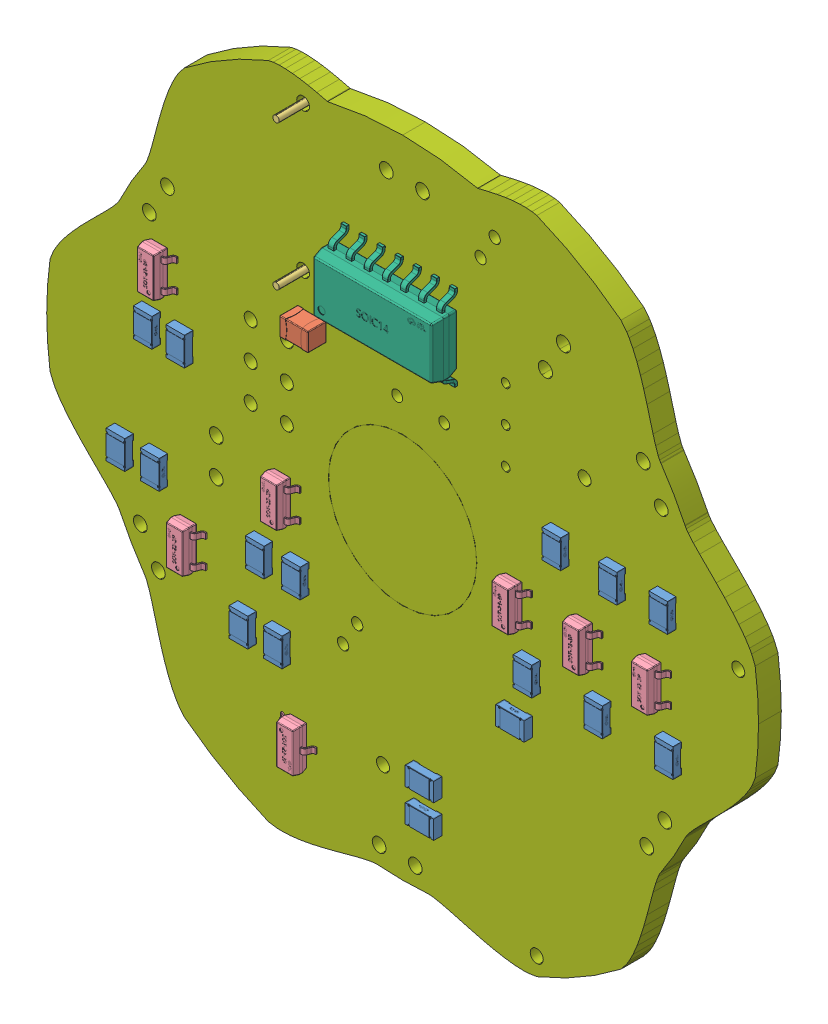
SolidWorks assembly PCB3d, configuration Default. Lengths in mm.
Overall size (49.97 46.56 5.9).
86 component instances, 7 part files, 0 mates.
Components (placement in the parent):
- 3D_PCB_PCB_Segnalatore copy copy_2023-08-18_2023-08-18.step-1: 3D_PCB_PCB_Segnalatore copy copy_2023-08-18_2023-08-18.step [Default] at origin size (49.97 46.56 5.9)
  - R5.step-1: R5.step [Default] at (9.525 -26.0351 1.6) x (-1 0 0) z (0 0 1) size (2 1.3 0.61)
    - R0805.step-1: R0805.step [Default] at origin size (2 1.3 0.61)
      - COMPOUND.step-1: COMPOUND.step [Default] at origin size (2 1.3 0.61)
  - R2.step-1: R2.step [Default] at (9.525 -28.3211 1.6) size (2 1.3 0.61)
    - R0805.step-1: R0805.step [Default] at origin size (2 1.3 0.61)
      - COMPOUND.step-1: COMPOUND.step [Default] at origin size (2 1.3 0.61)
  - R7.step-1: R7.step [Default] at (18.796 -7.112 1.6) x (0 -1 0) z (0 0 1) size (2 1.3 0.61)
    - R0805.step-1: R0805.step [Default] at origin size (2 1.3 0.61)
      - COMPOUND.step-1: COMPOUND.step [Default] at origin size (2 1.3 0.61)
  - R8.step-1: R8.step [Default] at (22.733 -7.239 1.6) x (0 -1 0) z (0 0 1) size (2 1.3 0.61)
    - R0805.step-1: R0805.step [Default] at origin size (2 1.3 0.61)
      - COMPOUND.step-1: COMPOUND.step [Default] at origin size (2 1.3 0.61)
  - R9.step-1: R9.step [Default] at (26.2891 -7.239 1.6) x (0 -1 0) z (0 0 1) size (2 1.3 0.61)
    - R0805.step-1: R0805.step [Default] at origin size (2 1.3 0.61)
      - COMPOUND.step-1: COMPOUND.step [Default] at origin size (2 1.3 0.61)
  - R10.step-1: R10.step [Default] at (-0.762 -22.86 1.6) x (0 -1 0) z (0 0 1) size (2 1.3 0.61)
    - R0805.step-1: R0805.step [Default] at origin size (2 1.3 0.61)
      - COMPOUND.step-1: COMPOUND.step [Default] at origin size (2 1.3 0.61)
  - R11.step-1: R11.step [Default] at (-9.398 -16.383 1.6) x (0 -1 0) z (0 0 1) size (2 1.3 0.61)
    - R0805.step-1: R0805.step [Default] at origin size (2 1.3 0.61)
      - COMPOUND.step-1: COMPOUND.step [Default] at origin size (2 1.3 0.61)
  - R12.step-1: R12.step [Default] at (-7.62 -8.001 1.6) x (0 1 0) z (0 0 1) size (2 1.3 0.61)
    - R0805.step-1: R0805.step [Default] at origin size (2 1.3 0.61)
      - COMPOUND.step-1: COMPOUND.step [Default] at origin size (2 1.3 0.61)
  - R13.step-1: R13.step [Default] at (-2.032 -18.034 1.6) x (0 1 0) z (0 0 1) size (2 1.3 0.61)
    - R0805.step-1: R0805.step [Default] at origin size (2 1.3 0.61)
      - COMPOUND.step-1: COMPOUND.step [Default] at origin size (2 1.3 0.61)
  - R15.step-1: R15.step [Default] at (16.764 -15.875 1.6) x (0 -1 0) z (0 0 1) size (2 1.3 0.61)
    - R0805.step-1: R0805.step [Default] at origin size (2 1.3 0.61)
      - COMPOUND.step-1: COMPOUND.step [Default] at origin size (2 1.3 0.61)
  - R16.step-1: R16.step [Default] at (21.717 -15.875 1.6) x (0 -1 0) z (0 0 1) size (2 1.3 0.61)
    - R0805.step-1: R0805.step [Default] at origin size (2 1.3 0.61)
      - COMPOUND.step-1: COMPOUND.step [Default] at origin size (2 1.3 0.61)
  - R17.step-1: R17.step [Default] at (26.6701 -15.875 1.6) x (0 -1 0) z (0 0 1) size (2 1.3 0.61)
    - R0805.step-1: R0805.step [Default] at origin size (2 1.3 0.61)
      - COMPOUND.step-1: COMPOUND.step [Default] at origin size (2 1.3 0.61)
  - R18.step-1: R18.step [Default] at (-3.175 -22.86 1.6) x (0 1 0) z (0 0 1) size (2 1.3 0.61)
    - R0805.step-1: R0805.step [Default] at origin size (2 1.3 0.61)
      - COMPOUND.step-1: COMPOUND.step [Default] at origin size (2 1.3 0.61)
  - R19.step-1: R19.step [Default] at (-11.811 -16.383 1.6) x (0 1 0) z (0 0 1) size (2 1.3 0.61)
    - R0805.step-1: R0805.step [Default] at origin size (2 1.3 0.61)
      - COMPOUND.step-1: COMPOUND.step [Default] at origin size (2 1.3 0.61)
  - R20.step-1: R20.step [Default] at (-9.906 -8.001 1.6) x (0 -1 0) z (0 0 1) size (2 1.3 0.61)
    - R0805.step-1: R0805.step [Default] at origin size (2 1.3 0.61)
      - COMPOUND.step-1: COMPOUND.step [Default] at origin size (2 1.3 0.61)
  - R21.step-1: R21.step [Default] at (0.508 -18.034 1.6) x (0 -1 0) z (0 0 1) size (2 1.3 0.61)
    - R0805.step-1: R0805.step [Default] at origin size (2 1.3 0.61)
      - COMPOUND.step-1: COMPOUND.step [Default] at origin size (2 1.3 0.61)
  - R22.step-1: R22.step [Default] at (15.875 -19.177 1.6) size (2 1.3 0.61)
    - R0805.step-1: R0805.step [Default] at origin size (2 1.3 0.61)
      - COMPOUND.step-1: COMPOUND.step [Default] at origin size (2 1.3 0.61)
  - C1.step-1: C1.step [Default] at (1.397 -2.413 1.6) x (-1 0 0) z (0 0 1) size (2 1.3 1.3)
    - C0805.step-1: C0805.step [Default] at origin size (2 1.3 1.3)
      - SOLID.step-1: SOLID.step [Default] at origin size (2 1.3 1.3)
  - R3.step-1: R3.step [Default] at (0.762 5.588 0) x (0 1 0) z (0 0 -1) size (10.6 2.32 5.8)
    - R_AXIAL-0.4.step-1: R_AXIAL-0.4.step [Default] at origin size (10.6 2.32 5.8)
      - SOLID-0.step-1: SOLID-0.step [Default] at origin size (10.6 2.32 5.8)
  - Q1.step-1: Q1.step [Default] at (15.621 -12.065 1.6) size (2.51 2.9 1.05)
    - SOT-23_L2.9-W1.3-P0.95-LS2.4-BR.step-1: SOT-23_L2.9-W1.3-P0.95-LS2.4-BR.step [Default] at origin size (2.51 2.9 1.05)
      - COMPOUND-1.step-1: COMPOUND-1.step [Default] at origin size (2.51 2.9 1.05)
  - Q2.step-1: Q2.step [Default] at (20.574 -12.065 1.6) size (2.51 2.9 1.05)
    - SOT-23_L2.9-W1.3-P0.95-LS2.4-BR.step-1: SOT-23_L2.9-W1.3-P0.95-LS2.4-BR.step [Default] at origin size (2.51 2.9 1.05)
      - COMPOUND-1.step-1: COMPOUND-1.step [Default] at origin size (2.51 2.9 1.05)
  - Q3.step-1: Q3.step [Default] at (25.4001 -12.065 1.6) size (2.51 2.9 1.05)
    - SOT-23_L2.9-W1.3-P0.95-LS2.4-BR.step-1: SOT-23_L2.9-W1.3-P0.95-LS2.4-BR.step [Default] at origin size (2.51 2.9 1.05)
      - COMPOUND-1.step-1: COMPOUND-1.step [Default] at origin size (2.51 2.9 1.05)
  - Q4.step-1: Q4.step [Default] at (0.508 -28.1941 1.6) x (-1 0 0) z (0 0 1) size (2.51 2.9 1.05)
    - SOT-23_L2.9-W1.3-P0.95-LS2.4-BR.step-1: SOT-23_L2.9-W1.3-P0.95-LS2.4-BR.step [Default] at origin size (2.51 2.9 1.05)
      - COMPOUND-1.step-1: COMPOUND-1.step [Default] at origin size (2.51 2.9 1.05)
  - Q5.step-1: Q5.step [Default] at (-7.239 -19.939 1.6) size (2.51 2.9 1.05)
    - SOT-23_L2.9-W1.3-P0.95-LS2.4-BR.step-1: SOT-23_L2.9-W1.3-P0.95-LS2.4-BR.step [Default] at origin size (2.51 2.9 1.05)
      - COMPOUND-1.step-1: COMPOUND-1.step [Default] at origin size (2.51 2.9 1.05)
  - Q6.step-1: Q6.step [Default] at (-9.271 -4.191 1.6) size (2.51 2.9 1.05)
    - SOT-23_L2.9-W1.3-P0.95-LS2.4-BR.step-1: SOT-23_L2.9-W1.3-P0.95-LS2.4-BR.step [Default] at origin size (2.51 2.9 1.05)
      - COMPOUND-1.step-1: COMPOUND-1.step [Default] at origin size (2.51 2.9 1.05)
  - Q7.step-1: Q7.step [Default] at (-0.635 -13.843 1.6) size (2.51 2.9 1.05)
    - SOT-23_L2.9-W1.3-P0.95-LS2.4-BR.step-1: SOT-23_L2.9-W1.3-P0.95-LS2.4-BR.step [Default] at origin size (2.51 2.9 1.05)
      - COMPOUND-1.step-1: COMPOUND-1.step [Default] at origin size (2.51 2.9 1.05)
  - U2.step-1: U2.step [Default] at (-3.937 1.778 0) x (-1 0 0) z (0 0 -1) size (4.81 6 1.72)
    - SOIC-8_L5.0-W4.0-P1.27-LS6.0-BL-EP2.0.step-1: SOIC-8_L5.0-W4.0-P1.27-LS6.0-BL-EP2.0.step [Default] at origin size (4.81 6 1.72)
      - COMPOUND-2.step-1: COMPOUND-2.step [Default] at origin size (4.81 6 1.72)
  - U1.step-1: U1.step [Default] at (7.62 1.905 1.6) size (8.59 6 2)
    - SOIC-14_L8.7-W3.9-P1.27-LS6.0-BL.step-1: SOIC-14_L8.7-W3.9-P1.27-LS6.0-BL.step [Default] at origin size (8.59 6 2)
      - COMPOUND-3.step-1: COMPOUND-3.step [Default] at origin size (8.59 6 2)
  - COMPOUND-4.step-1: COMPOUND-4.step [Default] at origin size (49.97 46.56 1.6)
